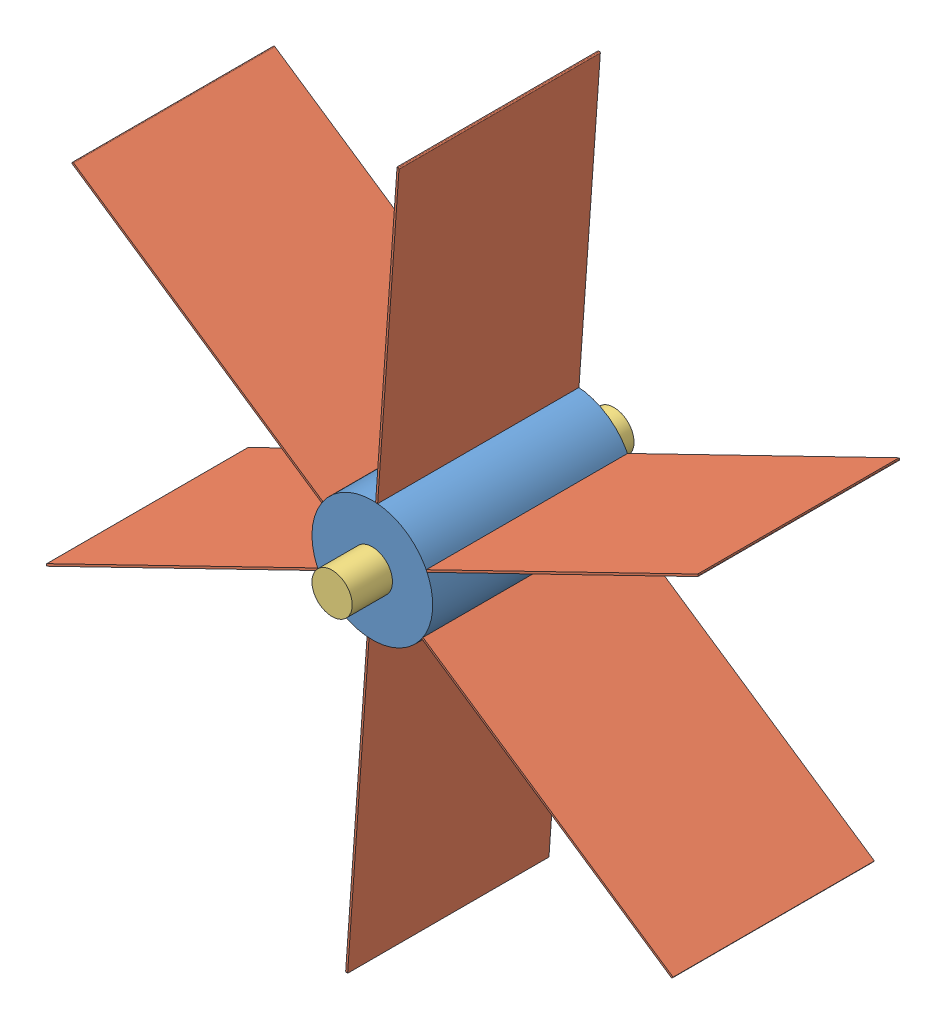
SolidWorks assembly Roue, configuration Défaut. Lengths in mm.
Overall size (162.09 179.58 70).
9 component instances, 3 part files, 7 mates.
Components (placement in the parent):
- Shaft-1: Shaft [Défaut] at (-6.7785 -1.8459 -25) size (30 30 50)
- Pale-1: Pale [Défaut] at (67.631 -52.4712 25) x (0 0 -1) z (0.560215 0.828347 0) size (50 75 0.5)
- Pale-2: Pale [Défaut] at (74.269 37.282 25) x (0 0 -1) z (-0.437263 0.899334 0) size (50 75 0.5)
- Pale-3: Pale [Défaut] at (-0.1405 87.9072 25) x (0 0 -1) z (-0.997477 0.070986 0) size (50 75 0.5)
- Pale-4: Pale [Défaut] at (-81.188 48.7793 25) x (0 0 -1) z (-0.560215 -0.828347 0) size (50 75 0.5)
- Pale-5: Pale [Défaut] at (-87.826 -40.9738 25) x (0 0 -1) z (0.437263 -0.899334 0) size (50 75 0.5)
- Pale-6: Pale [Défaut] at (-13.4165 -91.5991 25) x (0 0 -1) z (0.997477 -0.070986 0) size (50 75 0.5)
- Embout-2: Embout [Défaut] at (-6.7785 -1.8459 35) x (0 0 -1) z (0.995394 -0.095865 0) size (10 10 10)
- Embout-3: Embout [Défaut] at (-6.7785 -1.8459 -25) x (0 0 -1) z (1 0 0) size (10 10 10)
Mates (geometry in assembly coordinates):
- Coïncidente1: coincident: cylinder of Shaft-1 through (-6.7785 -1.8459 25) axis (0 0 -1) radius 15; line of Pale-1 through (5.7851 -10.0409 -25) axis (0 0 1)
- Coïncidente3: coincident: circle of Shaft-1; point of Pale-1
- Coïncidente4: coincident: cylinder of Shaft-1 through (-6.7785 -1.8459 25) axis (0 0 -1) radius 15; line of Pale-1 through (5.505 -10.4551 -25) axis (0 0 1)
- Coïncidente6: coincident anti-aligned: plane of Shaft-1 through (-6.7785 -1.8459 25) normal (0 0 1); plane of Embout-2 through (-6.7785 -1.8459 25) normal (0 0 -1)
- Coaxiale1: concentric anti-aligned: circle of Shaft-1; circle of Embout-2
- Coïncidente7: coincident anti-aligned: plane of Shaft-1 through (-6.7785 -1.8459 -25) normal (0 0 -1); plane of Embout-3 through (-6.7785 -1.8459 -25) normal (0 0 1)
- Coaxiale2: concentric anti-aligned: circle of Shaft-1; circle of Embout-3
